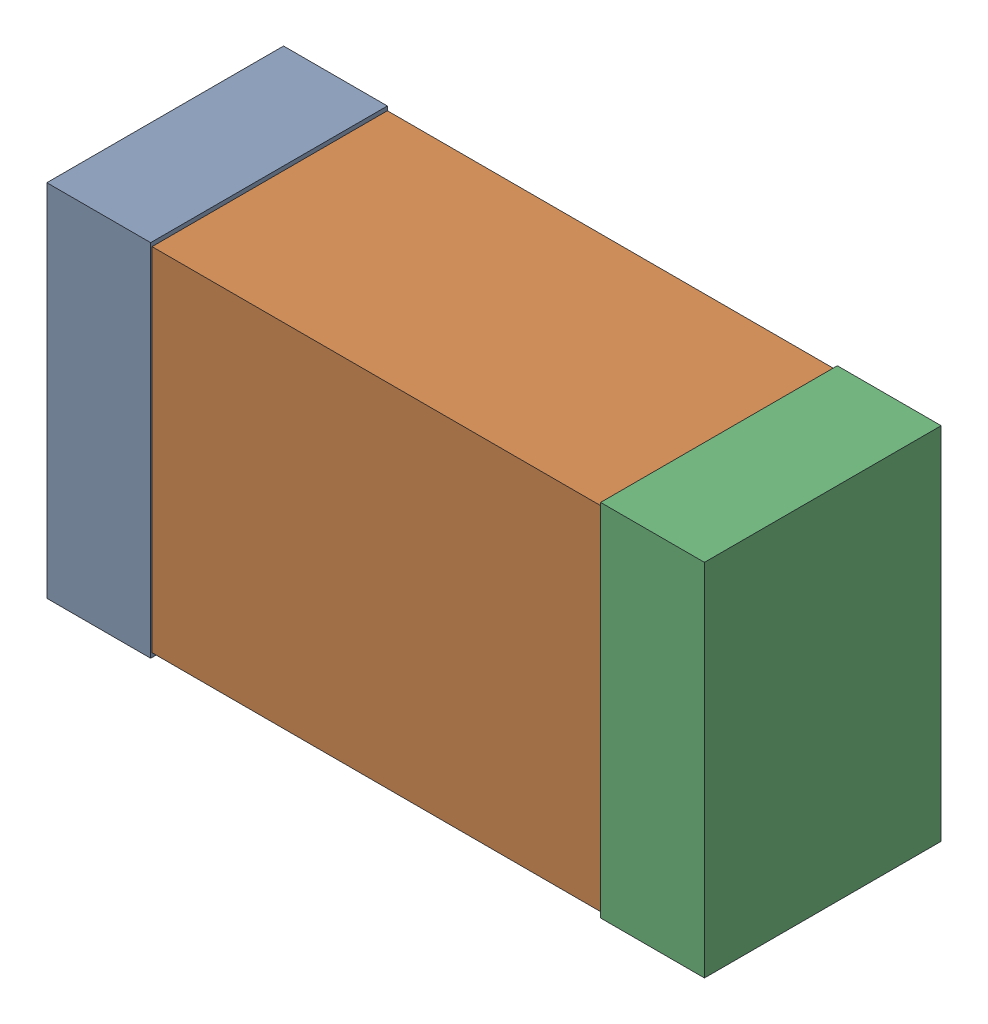
SolidWorks assembly USB23_C6, configuration Default. Lengths in mm.
Overall size (2.38 1.3 0.85).
6 component instances, 2 part files, 0 mates.
Components (placement in the parent):
- 384311232-1: 384311232 [Default] at (148.86 51.943 0) size (0.38 1.3 0.85)
  - Extruded_8-1: Extruded_8 [Default] at origin size (0.38 1.3 0.85)
- 402662800-1: 402662800 [Default] at (149.86 51.943 0) size (2.2 1.27 0.85)
  - Extruded_30-1: Extruded_30 [Default] at origin size (2.2 1.27 0.85)
- 384311232-2: 384311232 [Default] at (150.86 51.943 0) size (0.38 1.3 0.85)
  - Extruded_8-1: Extruded_8 [Default] at origin size (0.38 1.3 0.85)
